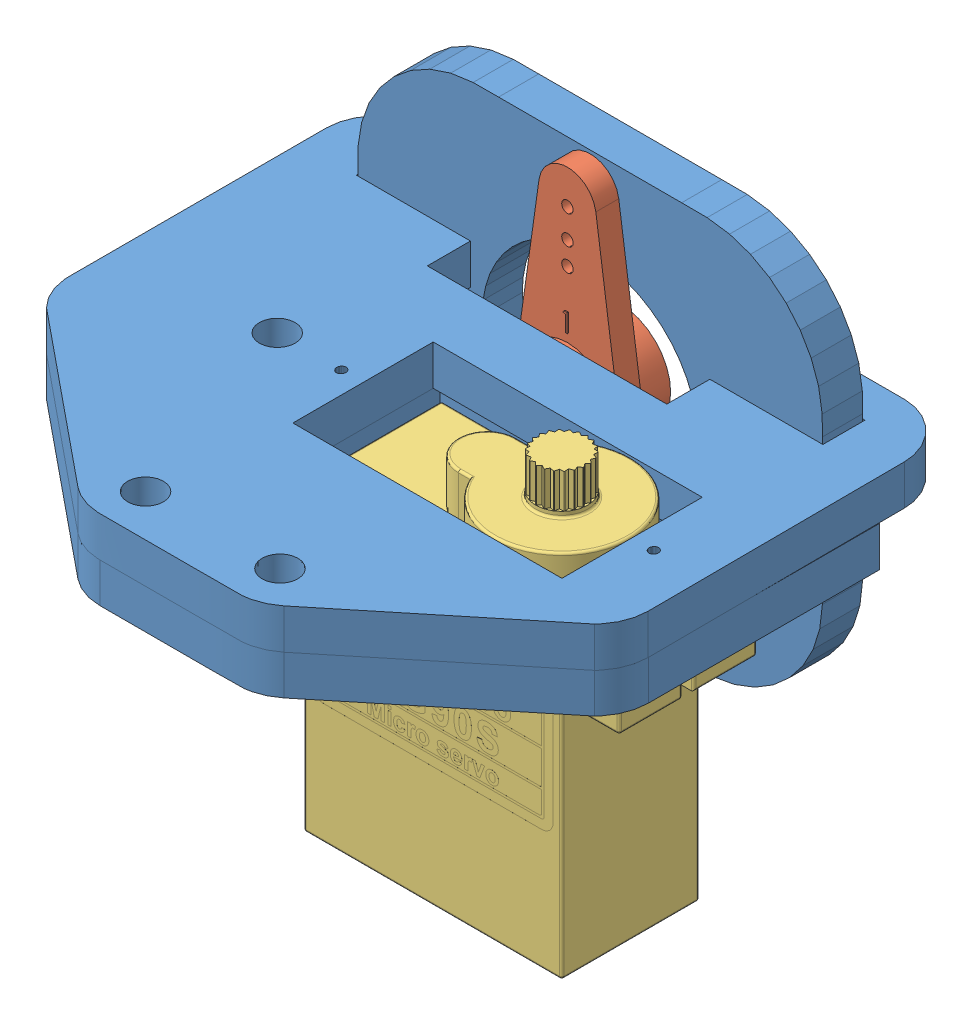
SolidWorks assembly left_wrist_100, configuration Default. Lengths in mm.
Overall size (51.63 42.56 44.74).
3 component instances, 3 part files, 1 mates.
Components (placement in the parent):
- left_wrist_100-1: left_wrist_100 [Default] at origin size (51.63 34.47 44.74)
- hs-422_horn_2wings_sws-1: hs-422_horn_2wings_sws [Default] at (20.2769 17.1817 3.5) x (1 0 0) z (0 -1 0) size (9.1 5 34)
- MG90s_servo-2: MG90s_servo [Default] at (27.9044 12.91 18.8749) x (1 0 0.000001) z (0 -1 0) size (32.5 12 34)
Mates (geometry in assembly coordinates):
- Coincident3: coincident aligned: plane of left_wrist100-1 through (20.2653 22.41 12.9868) normal (0 1 0); circle of MG90s_servo-2
